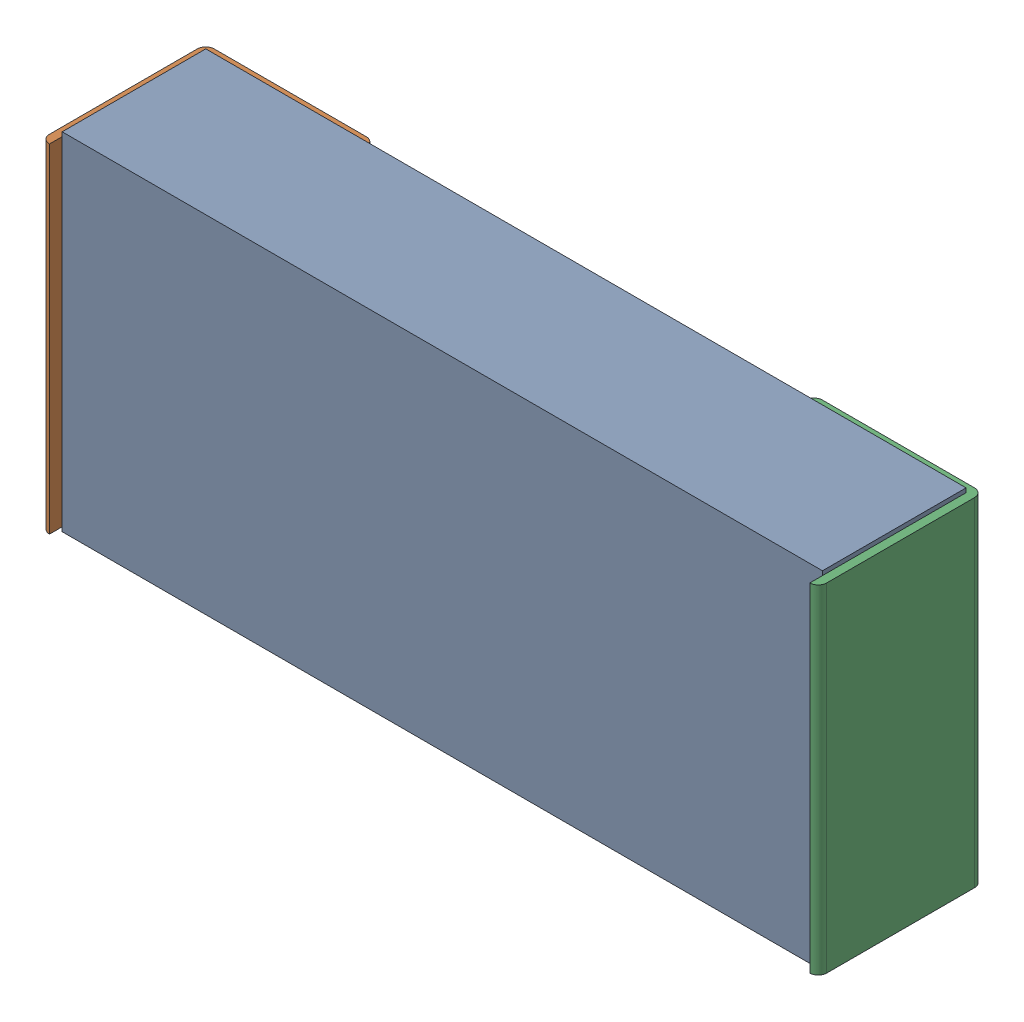
SolidWorks assembly C4, configuration Predeterminado. Lengths in mm.
Overall size (2.34 1.04 0.5).
4 component instances, 3 part files, 0 mates.
Components (placement in the parent):
- Open CASCADE STEP translator 6.8 1.5.1-1: Open CASCADE STEP translator 6.8 1.5.1 [Predeterminado] at origin size (2.34 1.04 0.5)
  - Body_1_2-1: Body_1_2 [Predeterminado] at origin size (2.29 1.04 0.43)
  - Pin_1_2-1: Pin_1_2 [Predeterminado] at (0.3048 0 0) x (-1 0 0) z (0 0 1) size (0.51 1.02 0.5)
  - Pin_2_2-1: Pin_2_2 [Predeterminado] at origin size (0.51 1.02 0.5)
